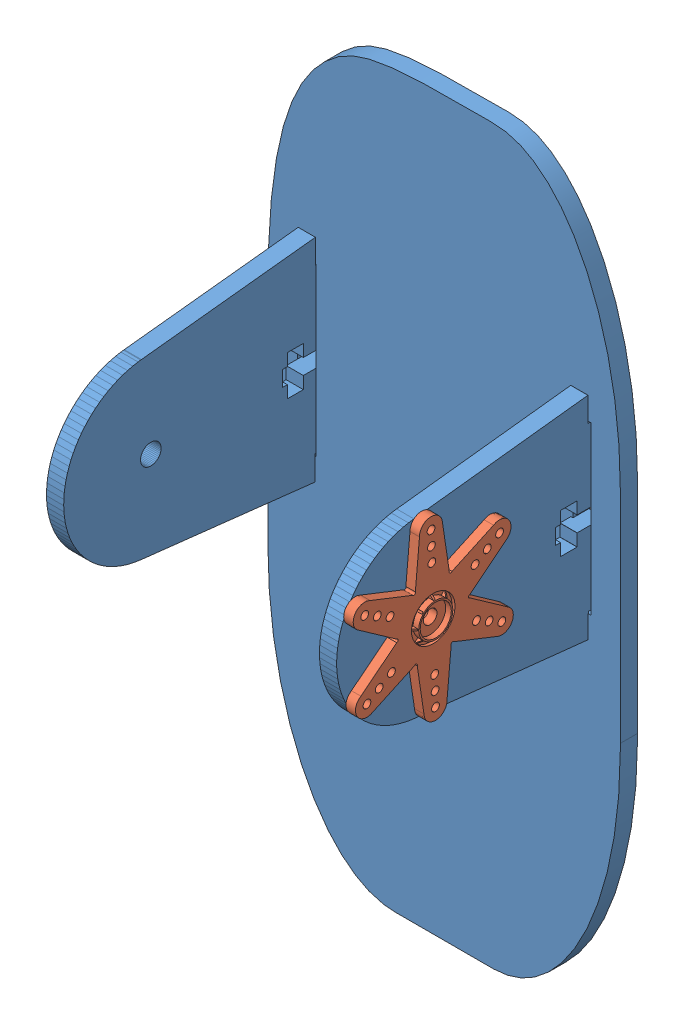
SolidWorks assembly right_foot, configuration Default. Lengths in mm.
Overall size (79.99 157.44 54.79).
2 component instances, 2 part files, 1 mates.
Components (placement in the parent):
- right_foot_100-1: right_foot_100 [Default] at origin size (79.99 157.44 54.79)
- servo_arm_6_sided-1: servo_arm_6_sided [Default] at (66.5071 90.4739 36.9765) x (0 0.999586 0.028771) z (0 0.028771 -0.999586) size (36.45 6.25 32.2)
Mates (geometry in assembly coordinates):
- ProfileCenter1: profile center aligned: circle of right_foot_100-1; circle of servo_arm_6_sided-1
